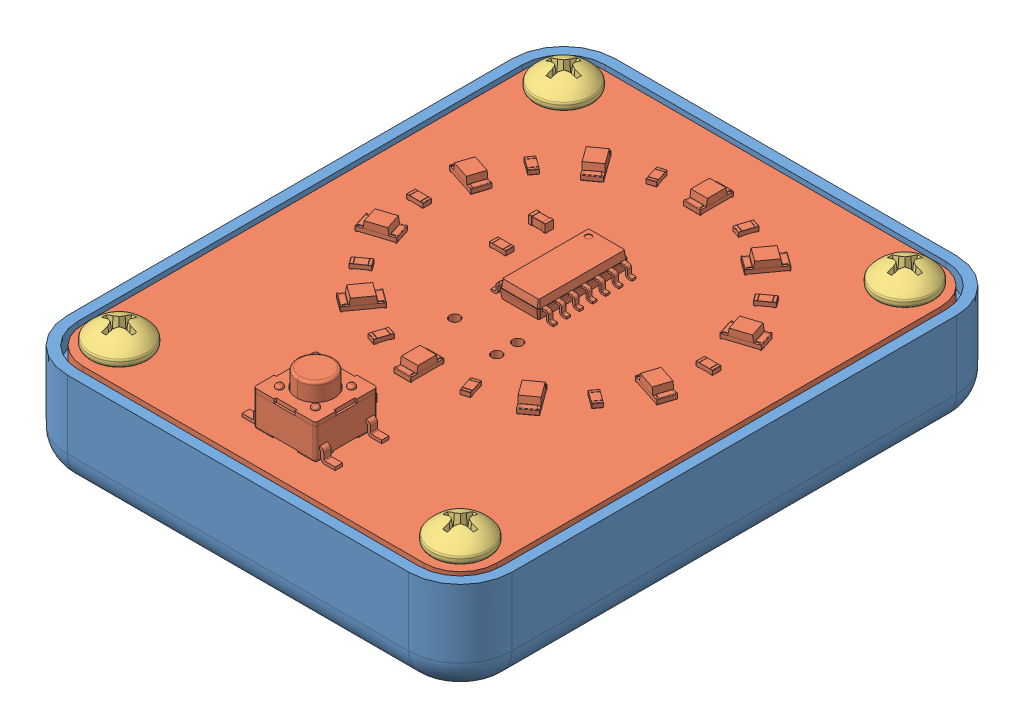
SolidWorks assembly ring_of_fire_assembly_rev_1, configuration Default. Lengths in mm.
Overall size (43 14.75 53).
6 component instances, 3 part files, 11 mates.
Components (placement in the parent):
- ring_of_fire_enclosure-1: ring_of_fire_enclosure [Default] at (7.0568 20.265 49.1596) x (1 0 0) z (0 1 0) size (43 53 9.6)
- ring_of_fire_pcba_rev_1a-1: ring_of_fire_pcba_rev_1a [Default] at (-92.9432 28.265 -50.8404) x (1 0 0) z (0 1 0) size (40 50 12.31)
- 92295A100_PHILLIPS THREAD-FORMING SCREW FOR PLASTIC-1: 92295A100_PHILLIPS THREAD-FORMING SCREW FOR PLASTIC [92295A100] at (-9.4432 26.69 70.6596) x (1 0 0) z (0 1 0) size (5.56 5.56 8.83)
- 92295A100_PHILLIPS THREAD-FORMING SCREW FOR PLASTIC-2: 92295A100_PHILLIPS THREAD-FORMING SCREW FOR PLASTIC [92295A100] at (23.5568 26.69 70.6596) x (1 0 0) z (0 1 0) size (5.56 5.56 8.83)
- 92295A100_PHILLIPS THREAD-FORMING SCREW FOR PLASTIC-3: 92295A100_PHILLIPS THREAD-FORMING SCREW FOR PLASTIC [92295A100] at (-9.4432 26.69 27.6596) x (1 0 0) z (0 1 0) size (5.56 5.56 8.83)
- 92295A100_PHILLIPS THREAD-FORMING SCREW FOR PLASTIC-4: 92295A100_PHILLIPS THREAD-FORMING SCREW FOR PLASTIC [92295A100] at (23.5568 26.69 27.6596) x (1 0 0) z (0 1 0) size (5.56 5.56 8.83)
Mates (geometry in assembly coordinates):
- Concentric2: concentric aligned: cylinder of ring_of_fire_enclosure-1 through (-9.4432 21.765 27.6596) axis (0 1 0) radius 1.25; cylinder of ring_of_fire_pcba_rev_1a-1 through (-9.4432 27.465 27.6596) axis (0 1 0) radius 1.6
- Concentric3: concentric aligned: cylinder of ring_of_fire_enclosure-1 through (23.5568 21.765 70.6596) axis (0 1 0) radius 1.25; cylinder of ring_of_fire_pcba_rev_1a-1 through (23.5568 27.465 70.6596) axis (0 1 0) radius 1.6
- Coincident1: coincident anti-aligned: plane of ring_of_fire_enclosure-1 through (-9.4432 28.265 70.6596) normal (0 1 0); plane of ring_of_fire_pcba_rev_1a-1 through (7.0568 28.265 49.1596) normal (0 -1 0)
- Concentric4: concentric anti-aligned: circle of ring_of_fire_enclosure-1; circle of 92295A100_PHILLIPS THREAD-FORMING SCREW FOR PLASTIC-1
- Coincident2: coincident anti-aligned: plane of ring_of_fire_pcba_rev_1a-1 through (7.0568 29.865 49.1596) normal (0 1 0); plane of 92295A100_PHILLIPS THREAD-FORMING SCREW FOR PLASTIC-1 through (-9.4432 29.865 70.6596) normal (0 -1 0)
- Concentric5: concentric anti-aligned: circle of ring_of_fire_enclosure-1; circle of 92295A100_PHILLIPS THREAD-FORMING SCREW FOR PLASTIC-2
- Coincident3: coincident anti-aligned: plane of ring_of_fire_pcba_rev_1a-1 through (7.0568 29.865 49.1596) normal (0 1 0); plane of 92295A100_PHILLIPS THREAD-FORMING SCREW FOR PLASTIC-2 through (23.5568 29.865 70.6596) normal (0 -1 0)
- Concentric6: concentric anti-aligned: circle of ring_of_fire_enclosure-1; circle of 92295A100_PHILLIPS THREAD-FORMING SCREW FOR PLASTIC-4
- Coincident4: coincident anti-aligned: plane of ring_of_fire_pcba_rev_1a-1 through (7.0568 29.865 49.1596) normal (0 1 0); plane of 92295A100_PHILLIPS THREAD-FORMING SCREW FOR PLASTIC-4 through (23.5568 29.865 27.6596) normal (0 -1 0)
- Concentric7: concentric anti-aligned: circle of ring_of_fire_enclosure-1; circle of 92295A100_PHILLIPS THREAD-FORMING SCREW FOR PLASTIC-3
- Coincident5: coincident anti-aligned: plane of ring_of_fire_pcba_rev_1a-1 through (7.0568 29.865 49.1596) normal (0 1 0); plane of 92295A100_PHILLIPS THREAD-FORMING SCREW FOR PLASTIC-3 through (-9.4432 29.865 27.6596) normal (0 -1 0)
